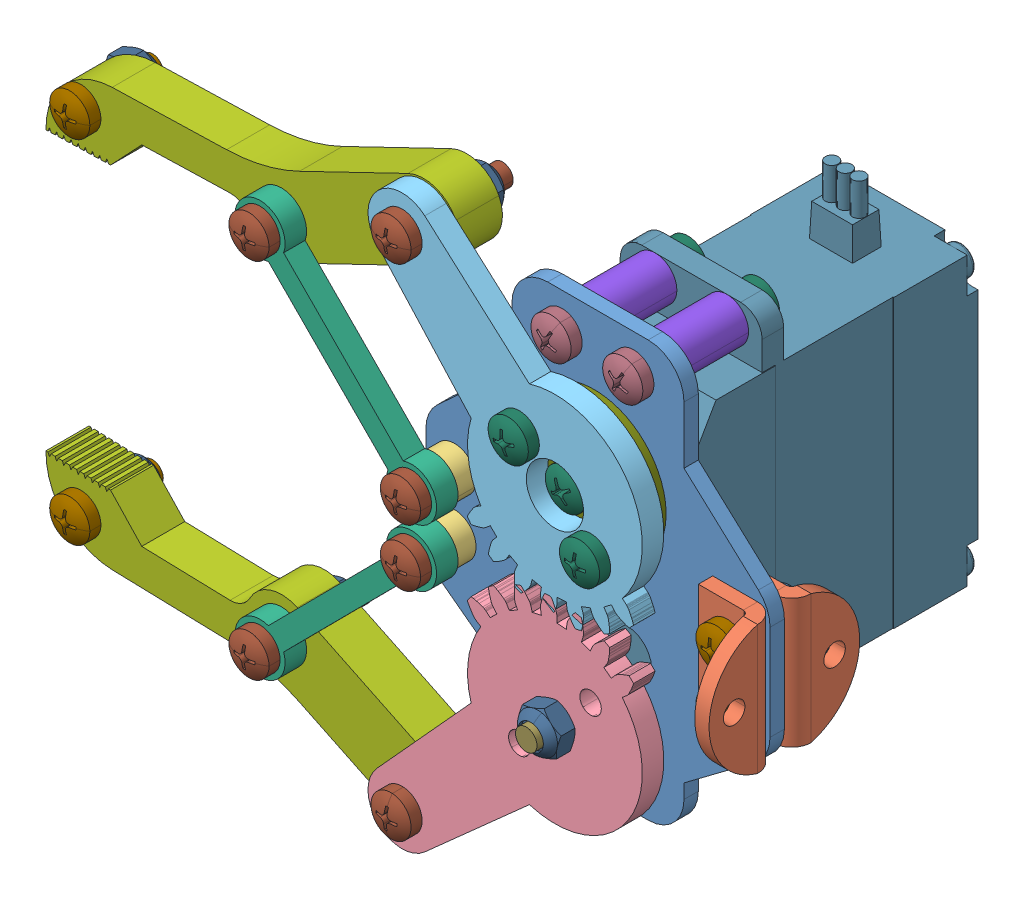
SolidWorks assembly 合金爪子含舵机, configuration 默认. Lengths in mm.
Overall size (101.41 100.28 53).
53 component instances, 16 part files, 20 mates.
Components (placement in the parent):
- 合金机械爪-1: 合金机械爪 [默认] at (91.9052 49.0306 100.9143) size (101.41 100.28 23)
  - 合金机械爪.STEP-1: 合金机械爪.STEP [默认] at (-14.0198 4.6103 -0.7994) size (101.41 100.28 23)
    - ____ ______.STEP-1: ____ ______.STEP [默认] at origin size (48 58 2)
    - ______.STEP-1: ______.STEP [默认] at (33 -61 -2) x (0 1 0) z (0 0 -1) size (18 9 9.5)
    - ______.STEP-2: ______.STEP [默认] at (33 -43 4) x (0 -1 0) z (0 0 1) size (18 9 9.5)
    - ______-0.STEP-1: ______-0.STEP [默认] at (8 -65.75 2) size (6 6 3)
    - ________ 2.STEP-1: ________ 2.STEP [默认] at (56.9021 -74.7915 5) x (-0.703683 0.710514 0) z (0.710514 0.703683 0) size (27.09 3 49.76)
    - ________.STEP-1: ________.STEP [默认] at (56.9021 -29.2085 8) x (-0.703683 -0.710514 0) z (0.710514 -0.703683 0) size (27.09 3 49.76)
    - ______-0.STEP-2: ______-0.STEP [默认] at (-12 -48 2) x (0.965012 -0.262207 0) z (0 0 1) size (6 6 3)
    - ______-0.STEP-3: ______-0.STEP [默认] at (-12 -56 2) x (-0.014061 0.999901 0) z (0 0 1) size (6 6 3)
    - ______-1.STEP-1: ______-1.STEP [默认] at (-33.1284 -26.7023 5) x (0.704279 -0.709924 0) z (0 0 1) size (37 7 3)
    - ____.STEP-1: ____.STEP [默认] at (-23.2219 -21.9209 -1) x (-0.900589 -0.434672 0) z (0 0 1) size (59.16 19.55 6)
    - ______-1.STEP-2: ______-1.STEP [默认] at (-33.1284 -77.2977 5) x (0.704279 0.709924 0) z (0 0 1) size (37 7 3)
    - ____.STEP-2: ____.STEP [默认] at (-23.2219 -82.0791 5) x (-0.900589 0.434672 0) z (0 0 -1) size (59.16 19.55 6)
    - ____-2.STEP-1: ____-2.STEP [默认] at (13 -24 -11) x (0 0 1) z (-0.999487 0.032029 0) size (11 6 6)
    - ____-2.STEP-2: ____-2.STEP [默认] at (13 -72 -11) x (0 0 1) z (-0.999487 0.032029 0) size (11 6 6)
    - ____-2.STEP-3: ____-2.STEP [默认] at (3 -24 -11) x (0 0 1) z (-0.999487 0.032029 0) size (11 6 6)
    - ____-2.STEP-4: ____-2.STEP [默认] at (3 -72 -11) x (0 0 1) z (-0.999487 0.032029 0) size (11 6 6)
    - GB818-M3X10-ZN-4.8.STEP-1: GB818-M3X10-ZN-4.8.STEP [默认] at (-61.1172 -27.4923 -5) size (5.6 5.6 12.4)
    - GB818-M3X10-ZN-4.8.STEP-2: GB818-M3X10-ZN-4.8.STEP [默认] at (-61.1172 -76.5077 -5) size (5.6 5.6 12.4)
    - GB6170-M3________.STEP-1: GB6170-M3________.STEP [默认] at (-61.1172 -76.5077 -3.4) x (-0.982663 0.185403 0) z (0 0 -1) size (6.36 6.36 3.39)
    - GB6170-M3________.STEP-2: GB6170-M3________.STEP [默认] at (-61.1172 -27.4923 -3.4) x (-0.982663 0.185403 0) z (0 0 -1) size (6.36 6.36 3.39)
    - GB6170-M3________.STEP-3: GB6170-M3________.STEP [默认] at (-33.1284 -77.2977 -3.4) x (-0.982663 0.185403 0) z (0 0 -1) size (6.36 6.36 3.39)
    - GB818-M3X14-ZN-4.8.STEP-1: GB818-M3X14-ZN-4.8.STEP [默认] at (-33.1284 -77.2977 -6) size (5.6 5.6 16.4)
    - GB818-M3X14-ZN-4.8.STEP-2: GB818-M3X14-ZN-4.8.STEP [默认] at (-33.1284 -26.7023 -6) size (5.6 5.6 16.4)
    - GB6170-M3________.STEP-4: GB6170-M3________.STEP [默认] at (-33.1284 -26.7023 -3.4) x (-0.982663 0.185403 0) z (0 0 -1) size (6.36 6.36 3.39)
    - GB818-M3X14-ZN-4.8.STEP-3: GB818-M3X14-ZN-4.8.STEP [默认] at (-12 -56 -6) size (5.6 5.6 16.4)
    - GB818-M3X14-ZN-4.8.STEP-4: GB818-M3X14-ZN-4.8.STEP [默认] at (-12 -48 -6) size (5.6 5.6 16.4)
    - GB6170-M3________.STEP-5: GB6170-M3________.STEP [默认] at (-12 -56 -2.4) x (-0.982663 0.185403 0) z (0 0 -1) size (6.36 6.36 3.39)
    - GB6170-M3________.STEP-6: GB6170-M3________.STEP [默认] at (-12 -48 -2.4) x (-0.982663 0.185403 0) z (0 0 -1) size (6.36 6.36 3.39)
    - GB818-M3X14-ZN-4.8.STEP-5: GB818-M3X14-ZN-4.8.STEP [默认] at (-13.3154 -17.1395 -6) size (5.6 5.6 16.4)
    - GB818-M3X14-ZN-4.8.STEP-6: GB818-M3X14-ZN-4.8.STEP [默认] at (-13.3154 -86.8605 -6) x (-0.065587 -0.997847 0) z (0 0 1) size (5.6 5.6 16.4)
    - GB6170-M3________.STEP-7: GB6170-M3________.STEP [默认] at (-13.3154 -86.8605 -3.4) x (-0.982663 0.185403 0) z (0 0 -1) size (6.36 6.36 3.39)
    - GB6170-M3________.STEP-8: GB6170-M3________.STEP [默认] at (-13.3154 -17.1395 -3.4) x (-0.982663 0.185403 0) z (0 0 -1) size (6.36 6.36 3.39)
    - GB818-M3X12-ZN-4.8.STEP-1: GB818-M3X12-ZN-4.8.STEP [默认] at (8 -65.75 12) x (-0.739529 0.673125 0) z (0 0 -1) size (5.6 5.6 14.4)
    - GB6170-M3________.STEP-9: GB6170-M3________.STEP [默认] at (8 -65.75 10.4) x (0.978769 -0.204968 0) z (0 0 1) size (6.36 6.36 3.39)
    - GB818-M3X10-ZN-4.8.STEP-3: GB818-M3X10-ZN-4.8.STEP [默认] at (28 -56 -6) x (0.990768 0.135569 0) z (0 0 1) size (5.6 5.6 12.4)
    - GB818-M3X10-ZN-4.8.STEP-4: GB818-M3X10-ZN-4.8.STEP [默认] at (28 -48 -6) x (0.990768 0.135569 0) z (0 0 1) size (5.6 5.6 12.4)
    - GB6170-M3________.STEP-10: GB6170-M3________.STEP [默认] at (28 -48 -4.4) x (-0.982663 0.185403 0) z (0 0 -1) size (6.36 6.36 3.39)
    - GB6170-M3________.STEP-11: GB6170-M3________.STEP [默认] at (28 -56 -4.4) x (-0.982663 0.185403 0) z (0 0 -1) size (6.36 6.36 3.39)
    - GB818-M3X6-ZN-4.8.STEP-1: GB818-M3X6-ZN-4.8.STEP [默认] at (3 -72 -4) x (-0.452469 -0.89178 0) z (0 0 1) size (5.6 5.6 8.4)
    - GB818-M3X6-ZN-4.8.STEP-2: GB818-M3X6-ZN-4.8.STEP [默认] at (3 -24 -4) x (-0.452469 -0.89178 0) z (0 0 1) size (5.6 5.6 8.4)
    - GB818-M3X6-ZN-4.8.STEP-3: GB818-M3X6-ZN-4.8.STEP [默认] at (13 -72 -4) x (-0.452469 -0.89178 0) z (0 0 1) size (5.6 5.6 8.4)
    - GB818-M3X6-ZN-4.8.STEP-4: GB818-M3X6-ZN-4.8.STEP [默认] at (13 -24 -4) x (-0.452469 -0.89178 0) z (0 0 1) size (5.6 5.6 8.4)
- 单轴舵机-1: 单轴舵机 [默认] at (95.8854 5.6409 79.1148) x (0 0 1) z (-1 0 0) size (45 56 20)
- GB818-M3X6-ZN-4.8-1: GB818-M3X6-ZN-4.8 [Default] at (80.9118 20.3167 102.1148) x (0.97101 0.239041 0) z (0 0 1) size (5.6 5.6 8.4)
- 金属主舵盘-1: 金属主舵盘 [默认] at (85.8854 15.3909 105.1148) x (0.710514 -0.703683 0) z (0.703683 0.710514 0) size (20 4.5 20)
- GB818-M3X6-ZN-4.8-2: GB818-M3X6-ZN-4.8 [Default] at (90.859 10.4651 102.1148) size (5.6 5.6 8.4)
- GB818-M3X6-ZN-4.8-3: GB818-M3X6-ZN-4.8 [Default] at (80.8854 29.6409 92.1148) x (-0.850027 0.526739 0) z (0 0 -1) size (5.6 5.6 8.4)
- GB818-M3X6-ZN-4.8-4: GB818-M3X6-ZN-4.8 [Default] at (90.8854 29.6409 92.1148) x (-0.923728 -0.383049 0) z (0 0 -1) size (5.6 5.6 8.4)
- GB818-M3X6-ZN-4.8-5: GB818-M3X6-ZN-4.8 [Default] at (90.8854 -18.3591 92.1148) x (-0.923728 -0.383049 0) z (0 0 -1) size (5.6 5.6 8.4)
- GB818-M3X6-ZN-4.8-6: GB818-M3X6-ZN-4.8 [Default] at (80.8854 -18.3591 92.1148) x (-0.923728 -0.383049 0) z (0 0 -1) size (5.6 5.6 8.4)
- GB818-M3X6-ZN-4.8-7: GB818-M3X6-ZN-4.8 [Default] at (85.8854 15.3909 99.1148) x (0.521397 -0.853314 0) z (0 0 1) size (5.6 5.6 8.4)
Mates (geometry in assembly coordinates):
- 同心2: concentric: cylinder of assembly; cylinder of 合金机械爪-1/合金机械爪.STEP-1/________.STEP-1 through (85.8854 15.3909 105.1148) axis (0 0 1) radius 4; cylinder of 金属主舵盘-1 through (85.8854 15.3909 105.1148) axis (0 0 -1) radius 1.5
- 同心3: concentric: cylinder of assembly; cylinder of 合金机械爪-1/合金机械爪.STEP-1/________.STEP-1 through (80.9118 20.3167 105.1148) axis (0 0 1) radius 1.5; cylinder of 金属主舵盘-1 through (80.9118 20.3167 105.1148) axis (0 0 -1) radius 1.5
- 重合1: coincident: plane of assembly; plane of 合金机械爪-1/合金机械爪.STEP-1/________.STEP-1 through (74.9845 23.5784 105.1148) normal (0 0 -1); plane of 金属主舵盘-1 through (85.8854 15.3909 105.1148) normal (0 0 1)
- 同心4: concentric: cylinder of assembly; cylinder of 合金机械爪-1/合金机械爪.STEP-1/________.STEP-1 through (80.9118 20.3167 105.1148) axis (0 0 1) radius 1.5; cylinder of GB818-M3X6-ZN-4.8-1 through (80.9118 20.3167 108.1148) axis (0 0 -1) radius 1.5
- 重合2: coincident: plane of assembly; plane of 合金机械爪-1/合金机械爪.STEP-1/________.STEP-1 through (74.9845 23.5784 108.1148) normal (0 0 1); plane of GB818-M3X6-ZN-4.8-1 through (80.9118 20.3167 108.1148) normal (0 0 -1)
- 同心5: concentric: cylinder of assembly; cylinder of 合金机械爪-1/合金机械爪.STEP-1/________.STEP-1 through (90.859 10.4651 105.1148) axis (0 0 1) radius 1.5; cylinder of GB818-M3X6-ZN-4.8-2 through (90.859 10.4651 108.1148) axis (0 0 -1) radius 1.5
- 重合3: coincident: plane of assembly; plane of 合金机械爪-1/合金机械爪.STEP-1/________.STEP-1 through (74.9845 23.5784 108.1148) normal (0 0 1); plane of GB818-M3X6-ZN-4.8-2 through (90.859 10.4651 108.1148) normal (0 0 -1)
- 同心6: concentric: cylinder of assembly; cylinder of 合金机械爪-1/合金机械爪.STEP-1/____-2.STEP-3 through (80.8854 29.6409 100.1148) axis (0 0 -1) radius 1.5; cylinder of 单轴舵机-1 through (80.8854 29.6409 81.8148) axis (0 0 1) radius 2.25
- 同心7: concentric: cylinder of assembly; cylinder of 合金机械爪-1/合金机械爪.STEP-1/____-2.STEP-1 through (90.8854 29.6409 100.1148) axis (0 0 -1) radius 1.5; cylinder of 单轴舵机-1 through (90.8854 29.6409 81.8148) axis (0 0 1) radius 2.25
- 重合4: coincident: plane of assembly; plane of 合金机械爪-1/合金机械爪.STEP-1/____-2.STEP-3 through (80.8854 29.6409 89.1148) normal (0 0 -1); plane of 单轴舵机-1 through (75.9854 32.6409 89.1148) normal (0 0 1)
- 同心8: concentric: cylinder of assembly; cylinder of 合金机械爪-1/合金机械爪.STEP-1/____-2.STEP-3 through (80.8854 29.6409 100.1148) axis (0 0 -1) radius 1.5; cylinder of GB818-M3X6-ZN-4.8-3 through (80.8854 29.6409 86.1148) axis (0 0 1) radius 1.5
- 重合5: coincident anti-aligned: plane of 单轴舵机-1 through (95.7854 32.6409 86.1148) normal (0 0 -1); plane of GB818-M3X6-ZN-4.8-3 through (80.8854 29.6409 86.1148) normal (0 0 1)
- 重合6: coincident anti-aligned: plane of 单轴舵机-1 through (95.7854 32.6409 86.1148) normal (0 0 -1); plane of GB818-M3X6-ZN-4.8-4 through (90.8854 29.6409 86.1148) normal (0 0 1)
- 同心9: concentric: cylinder of assembly; cylinder of 合金机械爪-1/合金机械爪.STEP-1/____-2.STEP-1 through (90.8854 29.6409 100.1148) axis (0 0 -1) radius 1.5; cylinder of GB818-M3X6-ZN-4.8-4 through (90.8854 29.6409 86.1148) axis (0 0 1) radius 1.5
- 重合7: coincident anti-aligned: plane of 单轴舵机-1 through (95.7854 -21.3591 86.1148) normal (0 0 -1); plane of GB818-M3X6-ZN-4.8-6 through (80.8854 -18.3591 86.1148) normal (0 0 1)
- 同心10: concentric: cylinder of assembly; cylinder of 合金机械爪-1/合金机械爪.STEP-1/____-2.STEP-4 through (80.8854 -18.3591 100.1148) axis (0 0 -1) radius 1.5; cylinder of GB818-M3X6-ZN-4.8-6 through (80.8854 -18.3591 86.1148) axis (0 0 1) radius 1.5
- 重合8: coincident anti-aligned: plane of 单轴舵机-1 through (95.7854 -21.3591 86.1148) normal (0 0 -1); plane of GB818-M3X6-ZN-4.8-5 through (90.8854 -18.3591 86.1148) normal (0 0 1)
- 同心11: concentric: cylinder of assembly; cylinder of 合金机械爪-1/合金机械爪.STEP-1/____-2.STEP-2 through (90.8854 -18.3591 100.1148) axis (0 0 -1) radius 1.5; cylinder of GB818-M3X6-ZN-4.8-5 through (90.8854 -18.3591 86.1148) axis (0 0 1) radius 1.5
- 重合9: coincident aligned: circle of 金属主舵盘-1; cylinder of GB818-M3X6-ZN-4.8-7 through (85.8854 15.3909 105.1148) axis (0 0 -1) radius 1.5
- 重合10: coincident anti-aligned: plane of 金属主舵盘-1 through (85.8854 15.3909 105.1148) normal (0 0 1); plane of GB818-M3X6-ZN-4.8-7 through (85.8854 15.3909 105.1148) normal (0 0 -1)
